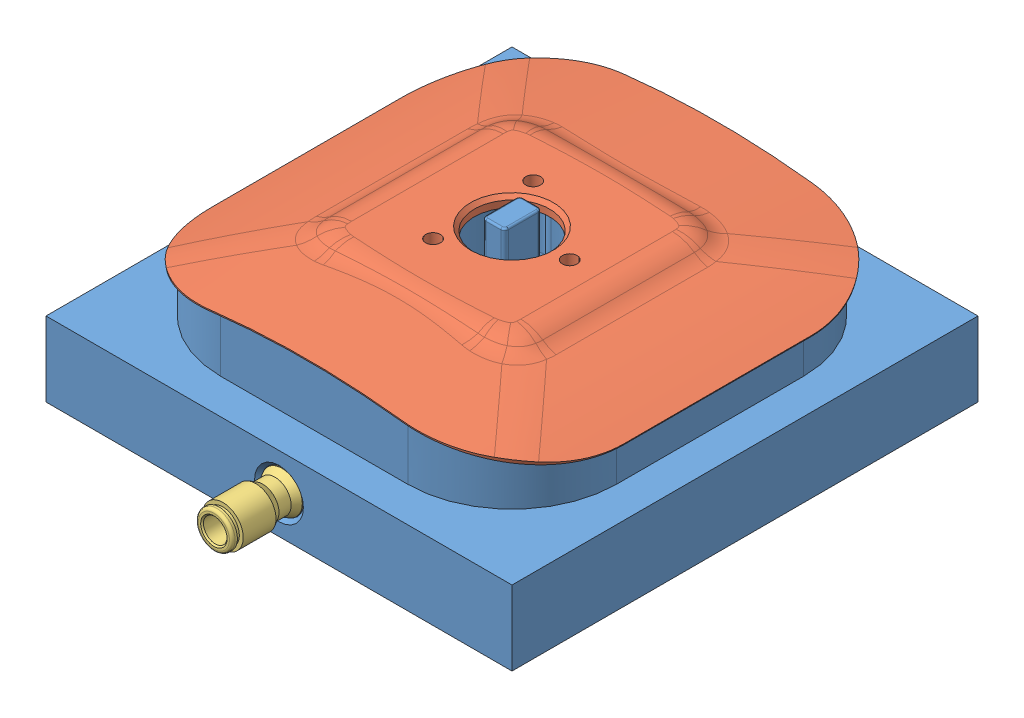
SolidWorks assembly PIT Foot Machining, configuration Default. Lengths in mm.
Overall size (125 44 142.46).
3 component instances, 3 part files, 9 mates.
Components (placement in the parent):
- PIT Foot Chuck-1: PIT Foot Chuck [Default] at origin size (125 44 125)
- PIT_foot_composit_v6-1: PIT_foot_composit_v6 [Default] at (0 -3.2 0) x (0 -1 0) z (0 0 1) size (12.8 113.62 113.59)
- 5779K140-1: 5779K140 [5779K14] at (0 -28 65.232) size (10.92 10.92 29.46)
Mates (geometry in assembly coordinates):
- Coincident1: coincident aligned: plane of PIT Foot Chuck-1 through (0 0 0) normal (0 0 1); plane of assembly through (0 0 0) normal (0 0 1)
- Coincident2: coincident aligned: plane of PIT Foot Chuck-1 through (0 0 0) normal (0 1 0); plane of assembly through (0 0 0) normal (0 1 0)
- Coincident3: coincident aligned: plane of PIT Foot Chuck-1 through (0 0 0) normal (1 0 0); plane of assembly through (0 0 0) normal (1 0 0)
- Coincident4: coincident aligned: plane of PIT_foot_composit_v6-1 through (0 -3.2 0) normal (0 0 1); plane of assembly through (0 0 0) normal (0 0 1)
- Perpendicular1: perpendicular: plane of PIT_foot_composit_v6-1; plane of assembly through (0 0 0) normal (1 0 0)
- Concentric1: concentric anti-aligned: cylinder of PIT Foot Chuck-1 through (0 -216.9433 164.6122) axis (0 0 -1) radius 216.2; cylinder of PIT_foot_composit_v6-1 through (0 -216.9433 -32.5) axis (0 0 1) radius 216.2
- Concentric2: concentric aligned: cylinder of PIT Foot Chuck-1 through (0 -28 50.5) axis (0 0 1) radius 5.5563; cylinder of 5779K140-1 through (0 -28 65.232) axis (0 0 1) radius 5.461
- Coincident6: coincident anti-aligned: plane of PIT Foot Chuck-1 through (0 -28 50.5) normal (0 0 1); plane of 5779K140-1 through (0 -23.8471 50.5) normal (0 0 -1)
- Parallel1: parallel aligned: plane of 5779K140-1 through (0 -28 65.232) normal (1 0 0); plane of assembly through (0 0 0) normal (1 0 0)
